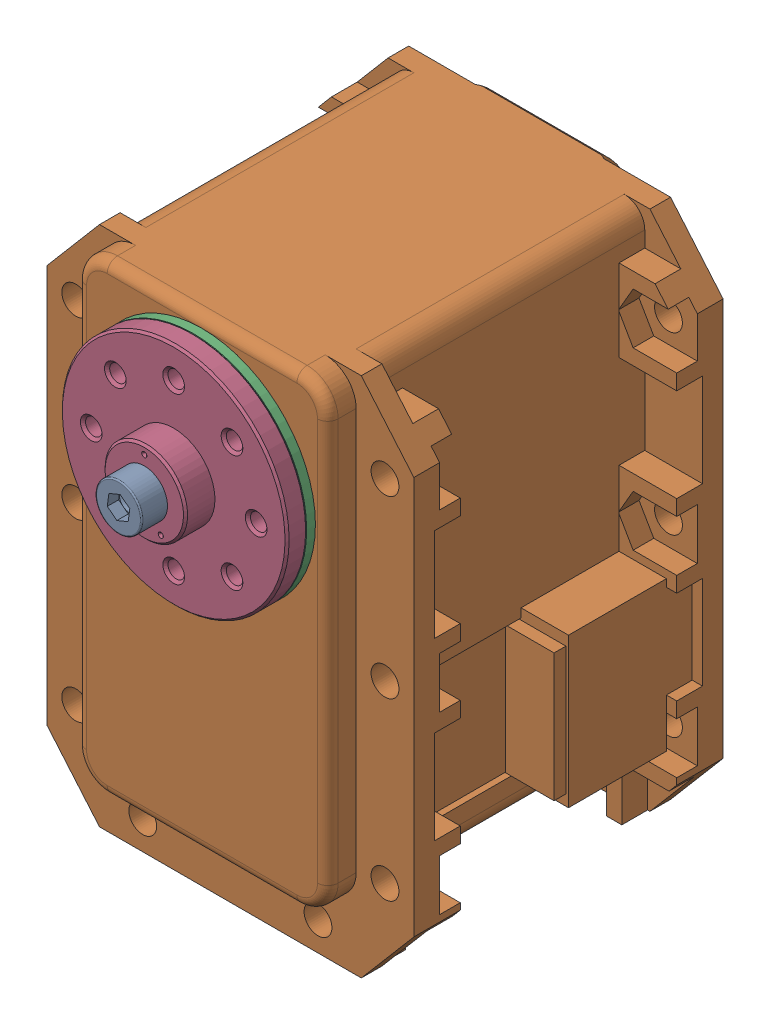
SolidWorks assembly MX-28(T)-6, configuration Default. Lengths in mm.
Overall size (35.6 54.13 45.1).
4 component instances, 4 part files, 0 mates.
Components (placement in the parent):
- WB_M2.5x8-1: WB_M2.5x8 [Default] at (0 0 25.85) x (0 0 -1) z (-0.991137 0.132843 0) size (10.5 4.5 4.5)
- dynamixel_x28series(Défaut)-1: dynamixel_x28series(Défaut) [Default] at origin size (35.6 50.71 41.85)
- trust_washer(Défaut)-1: trust_washer(Défaut) [Default] at (0 0 18.6) x (-0.666375 -0.745617 0) z (0.745617 -0.666375 0) size (22 0.85 22)
- HN07-N101(Défaut)-1: HN07-N101(Défaut) [Default] at (0 0 18.5) x (1 0 0) z (0 -1 0) size (22 5.85 22)
